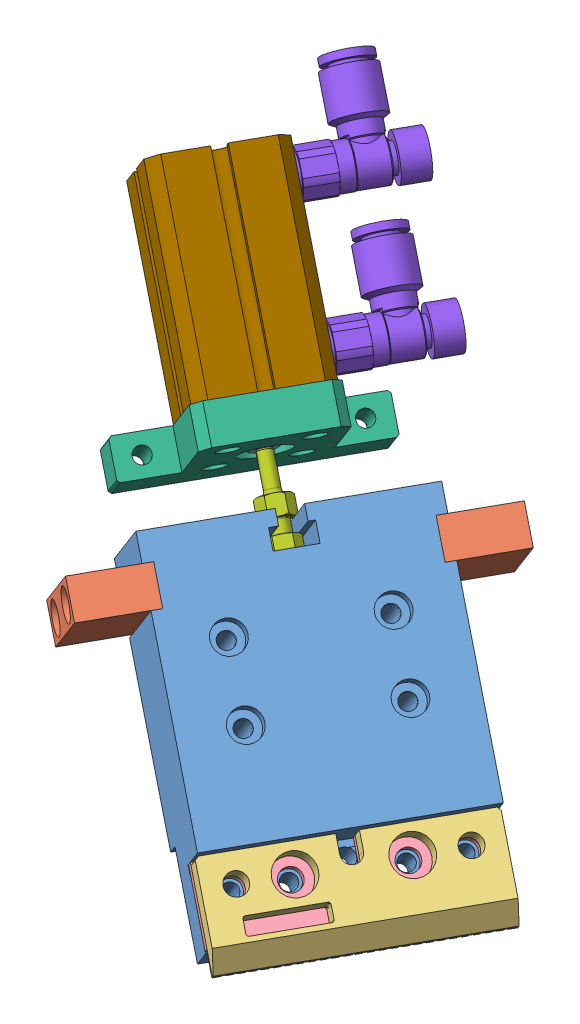
SolidWorks assembly assy FL_a0001, configuration Default. Lengths in mm.
Overall size (116.26 117.21 110.73).
11 component instances, 9 part files, 29 mates.
Components (placement in the parent):
- FL-0003-1: FL-0003 [Default] at (32.9495 -35897.9445 -137.3895) x (0.615964 -0.704373 0.35277) z (-0.523605 -0.031491 0.851379) size (70 25 52)
- FL-0004-1: FL-0004 [Default] at (-13.0625 -35905.598 -107.2421) x (0.615964 -0.704373 0.35277) z (-0.523605 -0.031491 0.851379) size (8 22 15)
- Fl-0006-1: Fl-0006 [Default] at (21.1726 -35946.3156 -85.3441) x (0.588579 0.709131 0.388211) z (0.523605 0.031491 -0.851379) size (5 20 52)
- FL-0005B-1: FL-0005B [Default] at (30.8644 -35942.3987 -109.3259) x (0.523605 0.031491 -0.851379) z (-0.588579 -0.709131 -0.388211) size (52 20 2.15)
- FL-0004-2: FL-0004 [Default] at (7.1428 -35898.4515 -150.9304) x (-0.615964 0.704373 -0.35277) z (0.523605 0.031491 -0.851379) size (8 22 15)
- cdqsb2-5: cdqsb2 [Default] at (-21.0564 -35887.601 -139.5563) x (-0.615964 0.704373 -0.35277) z (0.436536 -0.067571 -0.897146) size (39.5 12 12)
- FL-0001-9: FL-0001 [Default] at (-14.5852 -35887.9748 -140.2628) x (-0.523605 -0.031491 0.851379) z (-0.615964 0.704373 -0.35277) size (48 31 8)
- FJD3-0.5-3-2: FJD3-0.5-3 [Default] at (-7.8131 -35902.7451 -131.9717) x (-0.615964 0.704373 -0.35277) z (-0.77035 -0.44491 0.456744) size (18 6.94 7.74)
- AS1201F-3: AS1201F [Default] at (-21.5949 -35879.1071 -154.2553) x (0.588579 0.709131 0.388211) z (-0.615964 0.704373 -0.35277) size (10.4 26.5 23.4)
- cdqsb1-9: cdqsb1 [Default] at (-23.5202 -35884.7835 -140.9673) x (-0.615964 0.704373 -0.35277) z (-0.588579 -0.709131 -0.388211) size (42 25 25)
- AS1201F-7: AS1201F [Default] at (-39.7658 -35858.3281 -164.662) x (0.588579 0.709131 0.388211) z (-0.615964 0.704373 -0.35277) size (10.4 26.5 23.4)
Mates (geometry in assembly coordinates):
- Coincident8: coincident anti-aligned: plane of Fl-0006-1 through (50.0215 -35947.6767 -128.7296) normal (-0.588579 -0.709131 -0.388211); plane of FL-0005B-1 through (26.5691 -35937.2419 -112.2334) normal (0.588579 0.709131 0.388211)
- Concentric16: concentric aligned: cylinder of Fl-0006-1 through (-10.3511 -35972.5932 -112.7508) axis (0.588579 0.709131 0.388211) radius 2.25; cylinder of FL-0005B-1 through (16.0467 -35940.7887 -95.3396) axis (0.588579 0.709131 0.388211) radius 2.25
- Coincident10: coincident aligned: plane of Fl-0006-1 through (37.7022 -35933.5892 -135.785) normal (-0.615964 0.704373 -0.35277); plane of FL-0005B-1 through (23.8777 -35935.8692 -116.1988) normal (-0.615964 0.704373 -0.35277)
- Coincident11: coincident anti-aligned: plane of FL-0003-1 through (10.3695 -35938.0781 -91.6834) normal (0.588579 0.709131 0.388211); plane of FL-0005B-1 through (25.3036 -35938.7665 -113.0681) normal (-0.588579 -0.709131 -0.388211)
- Concentric19: concentric aligned: cylinder of FL-0003-1 through (16.0467 -35940.7887 -95.3396) axis (0.588579 0.709131 0.388211) radius 1.65; cylinder of Fl-0006-1 through (-10.3511 -35972.5932 -112.7508) axis (0.588579 0.709131 0.388211) radius 2.25
- Parallel7: parallel anti-aligned: plane of FL-0003-1 through (15.6256 -35929.5757 -88.1364) normal (0.615964 -0.704373 0.35277); plane of Fl-0006-1 through (37.7022 -35933.5892 -135.785) normal (-0.615964 0.704373 -0.35277)
- Coincident14: coincident anti-aligned: plane of FL-0003-1 through (-19.1673 -35930.1504 -168.2838) normal (0.523605 0.031491 -0.851379); plane of FL-0004-2 through (7.1428 -35898.4515 -150.9304) normal (-0.523605 -0.031491 0.851379)
- Concentric20: concentric aligned: cylinder of FL-0003-1 through (10.9598 -35899.6387 -148.6268) axis (0.523605 0.031491 -0.851379) radius 1.25; cylinder of FL-0004-2 through (10.9598 -35899.6387 -148.6268) axis (0.523605 0.031491 -0.851379) radius 1.75
- Concentric21: concentric aligned: cylinder of FL-0003-1 through (3.8969 -35908.1483 -153.2854) axis (0.523605 0.031491 -0.851379) radius 1.25; cylinder of FL-0004-2 through (3.8969 -35908.1483 -153.2854) axis (0.523605 0.031491 -0.851379) radius 1.75
- Coincident16: coincident anti-aligned: plane of FL-0003-1 through (-39.3726 -35937.2969 -124.5955) normal (-0.523605 -0.031491 0.851379); plane of FL-0004-1 through (-13.0625 -35905.598 -107.2421) normal (0.523605 0.031491 -0.851379)
- Concentric22: concentric aligned: cylinder of FL-0003-1 through (-14.1732 -35901.1503 -107.7606) axis (-0.523605 -0.031491 0.851379) radius 1.25; cylinder of FL-0004-1 through (-14.1732 -35901.1503 -107.7606) axis (-0.523605 -0.031491 0.851379) radius 1.75
- Concentric23: concentric aligned: cylinder of FL-0003-1 through (-21.2362 -35909.6598 -112.4192) axis (-0.523605 -0.031491 0.851379) radius 1.25; cylinder of FL-0004-1 through (-21.2362 -35909.6598 -112.4192) axis (-0.523605 -0.031491 0.851379) radius 1.75
- Parallel13: parallel anti-aligned: plane of FL-0003-1 through (-18.1292 -35890.976 -107.4681) normal (-0.615964 0.704373 -0.35277); plane of FL-0001-9 through (-14.5852 -35887.9748 -140.2628) normal (0.615964 -0.704373 0.35277)
- Concentric34: concentric aligned: cylinder of cdqsb2-5 through (-18.9005 -35890.0663 -138.3216) axis (0.615964 -0.704373 0.35277) radius 1.2295; cylinder of FJD3-0.5-3-2 through (-18.9005 -35890.0663 -138.3216) axis (0.615964 -0.704373 0.35277) radius 1.5
- Coincident24: coincident anti-aligned: plane of cdqsb2-5 through (-18.9005 -35890.0663 -138.3216) normal (0.615964 -0.704373 0.35277); plane of FJD3-0.5-3-2 through (-18.9005 -35890.0663 -138.3216) normal (-0.615964 0.704373 -0.35277)
- Concentric35: concentric anti-aligned: cylinder of cdqsb2-5 through (-18.9005 -35890.0663 -138.3216) axis (-0.615964 0.704373 -0.35277) radius 3; cylinder of FL-0001-9 through (-23.5202 -35884.7835 -140.9673) axis (0.615964 -0.704373 0.35277) radius 5
- Coincident25: coincident anti-aligned: plane of FL-0003-1 through (-34.478 -35929.2176 -146.7745) normal (0.615964 -0.704373 0.35277); plane of FJD3-0.5-3-2 through (-10.1553 -35902.2912 -135.48) normal (-0.615964 0.704373 -0.35277)
- Lock1: lock: unknown of FL-0003-1; unknown of FJD3-0.5-3-2
- Concentric43: concentric aligned: cylinder of cdqsb2-5 through (-18.9005 -35890.0663 -138.3216) axis (-0.615964 0.704373 -0.35277) radius 3; cylinder of cdqsb1-9 through (-23.5202 -35884.7835 -140.9673) axis (-0.615964 0.704373 -0.35277) radius 3
- LimitDistance2: limit distance = 10 mm aligned: plane of cdqsb2-5 through (-39.2965 -35858.004 -150.6608) normal (-0.615964 0.704373 -0.35277); plane of cdqsb1-9 through (-49.3907 -35855.1999 -155.7837) normal (-0.615964 0.704373 -0.35277)
- Concentric44: concentric aligned: circle of cdqsb1-9; cylinder of AS1201F-7 through (-41.3366 -35858.4226 -162.1079) axis (0.523605 0.031491 -0.851379) radius 2.5
- Coincident28: coincident anti-aligned: plane of cdqsb1-9 through (-11.0967 -35877.3075 -147.7323) normal (0.523605 0.031491 -0.851379); plane of AS1201F-7 through (-39.7658 -35858.3281 -164.662) normal (-0.523605 -0.031491 0.851379)
- Concentric45: concentric aligned: cylinder of AS1201F-3 through (-23.1657 -35879.2016 -151.7012) axis (0.523605 0.031491 -0.851379) radius 2.5; cylinder of cdqsb1-9 through (-21.5949 -35879.1071 -154.2553) axis (0.523605 0.031491 -0.851379) radius 2.067
- Coincident29: coincident anti-aligned: circle of AS1201F-3; plane of cdqsb1-9 through (-11.0967 -35877.3075 -147.7323) normal (0.523605 0.031491 -0.851379)
- Coincident31: coincident anti-aligned: plane of FL-0001-9 through (-19.5129 -35882.3398 -143.085) normal (-0.615964 0.704373 -0.35277); plane of cdqsb1-9 through (-23.5202 -35884.7835 -140.9673) normal (0.615964 -0.704373 0.35277)
- Parallel14: parallel aligned: plane of FL-0001-9 through (-8.9147 -35874.9782 -146.8915) normal (0.588579 0.709131 0.388211); plane of cdqsb1-9 through (-21.3925 -35876.2339 -127.6116) normal (0.588579 0.709131 0.388211)
- Parallel15: parallel aligned: plane of FL-0004-2 through (19.2929 -35892.8032 -160.8675) normal (-0.615964 0.704373 -0.35277); plane of AS1201F-3 through (-25.9832 -35865.5806 -172.3105) normal (-0.615964 0.704373 -0.35277)
- Parallel16: parallel aligned: plane of FL-0004-2 through (19.2929 -35892.8032 -160.8675) normal (-0.615964 0.704373 -0.35277); plane of AS1201F-7 through (-44.1541 -35844.8016 -182.7172) normal (-0.615964 0.704373 -0.35277)
- Parallel17: parallel aligned: plane of FL-0003-1 through (-27.9363 -35906.388 -121.1171) normal (-0.588579 -0.709131 -0.388211); plane of FL-0001-9 through (-21.401 -35896.6148 -168.2912) normal (-0.588579 -0.709131 -0.388211)
